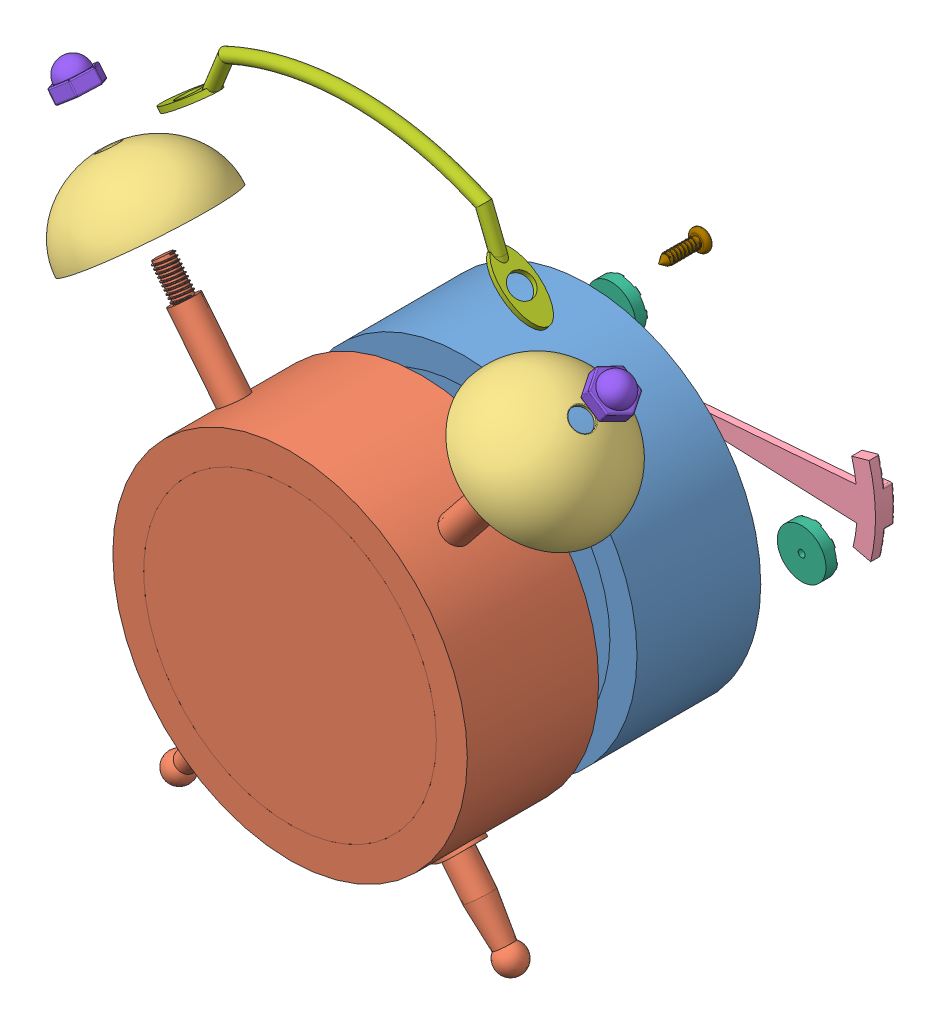
SolidWorks assembly m&m clock assembly exploded, configuration Default. Lengths in mm.
Overall size (94.51 97.82 76.89).
13 component instances, 9 part files, 15 mates.
Components (placement in the parent):
- inner body-1: inner body [Default] at origin size (49.9 49.9 19.3)
- clock casing-2: clock casing [Default] at (0 0 42.7593) size (94.51 65.37 40.11)
- bell-1: bell [Default] at (28.1459 35.1261 34.8593) x (0.7438 -0.595993 -0.302579) z (0.236127 -0.189204 0.953124) size (21.5 9.58 21.5)
- bell-2: bell [Default] at (-28.0236 34.9735 34.8593) x (0.724579 0.580592 0.371348) z (-0.289792 -0.232205 0.928494) size (21.5 9.58 21.5)
- alarm switch-2: alarm switch [Default] at (0 0 -16.4946) x (-0.999826 -0.018672 0) z (0 0 -1) size (25.97 12.5 2.77)
- battery lid-1: battery lid [Default] at (-6.5 -13.95 -12.6856) x (0.9986 -0.052899 0) z (0.052899 0.9986 0) size (13 3 13)
- dials-1: dials [Default] at (12.533 -11.5461 -18.2951) x (0.940835 -0.338864 0) z (0.338864 0.940835 0) size (7.02 1.74 7.02)
- dials-2: dials [Default] at (-11.5 8.45 -14.9521) x (0.046545 0.998916 0) z (-0.998916 0.046545 0) size (7.02 1.74 7.02)
- bell bar-5: bell bar [Default] at (0.2758 56.1834 33.6634) size (56.5 17.19 4.8)
- bell nut-2: bell nut [Default] at (37.6911 47.0385 34.8593) x (-0.116049 0.092988 -0.988881) z (0.771704 -0.618352 -0.148708) size (5.59 5.44 6.16)
- bell nut-3: bell nut [Default] at (-37.8802 47.2744 34.8593) x (0.760515 0.609387 0.224197) z (-0.174959 -0.140191 0.974544) size (5.59 5.44 6.16)
- screw-2: screw [Default] at (0 22.2891 -15.7365) x (0.763118 0.646259 0) z (-0.646259 0.763118 0) size (3 6.5 3)
- screw-3: screw [Default] at (0 -22.2891 -16.9017) x (-0.347944 0.937515 0) z (-0.937515 -0.347944 0) size (3 6.5 3)
Mates (geometry in assembly coordinates):
- Concentric2: concentric aligned: cylinder of clock face + plastic-1 through (0 0 17.8) axis (0 0 -1) radius 24.95; cylinder of main body-2 through (0 0 42.2593) axis (0 0 -1) radius 25
- Concentric7: concentric aligned: cylinder of clock face + plastic-1 through (0 0 -1) axis (0 0 1) radius 0.5; cylinder of alarm switch-2 through (0 0 -17.4946) axis (0 0 1) radius 0.5
- Concentric8: concentric aligned: cylinder of clock face + plastic-1 through (12.533 -11.5461 -1) axis (0 0 1) radius 0.5; cylinder of dials-1 through (12.533 -11.5461 -19.2951) axis (0 0 1) radius 0.5
- Concentric9: concentric aligned: cylinder of clock face + plastic-1 through (-11.5 8.45 -1) axis (0 0 1) radius 0.5; cylinder of dials-2 through (-11.5 8.45 -15.9521) axis (0 0 1) radius 0.5
- Parallel1: parallel: plane of main body-2 through (0 0 34.8593) normal (0 0 1); line of bell bar-5 through (-24.4892 56.1834 33.6634) axis (1 0 0)
- Concentric22: concentric aligned: circle of main body-2; circle of bell nut+bolt-2
- Concentric24: concentric anti-aligned: circle of main body-2; circle of bell nut+bolt-3
- Parallel4: parallel: line of main body-2 through (-45.6453 -31.2 34.8593) axis (1 0 0)
- Perpendicular2: perpendicular: line of main body-2 through (-45.6453 -31.2 34.8593) axis (1 0 0)
- Concentric25: concentric aligned: circle of clock face + plastic-1; circle of screw-2
- Concentric26: concentric aligned: circle of clock face + plastic-1; circle of screw-3
- Perpendicular3: perpendicular: line of clock casing-2 through (0 0 34.8593) axis (0 -1 0); line of bell bar-5 through (-24.4892 56.1834 33.6634) axis (1 0 0)
- Concentric27: concentric aligned: circle of clock casing-2; circle of bell-2
- Concentric28: concentric anti-aligned: circle of clock casing-2; circle of bell-1
- Concentric29: concentric aligned: circle of inner body-1; circle of battery lid-1
